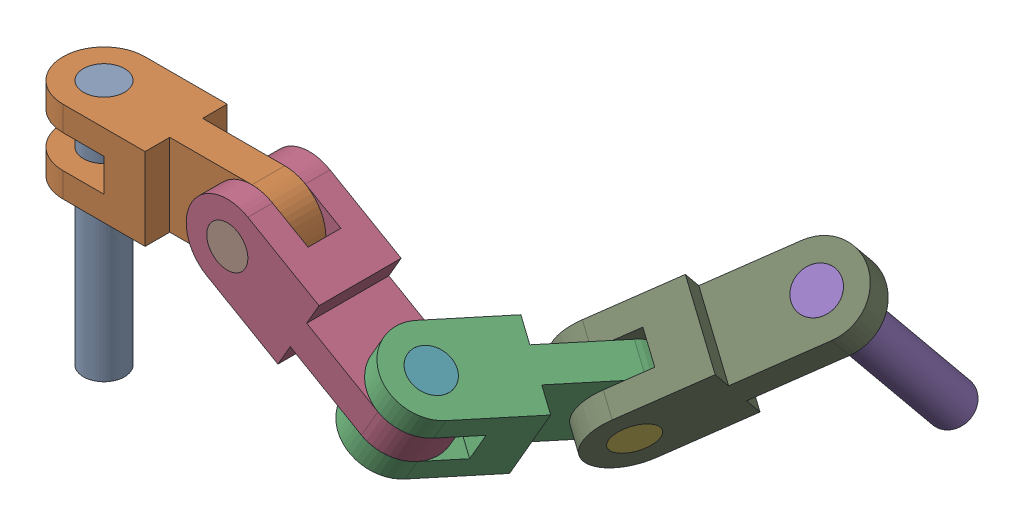
SolidWorks assembly Assemblage1 - Copie, configuration Défaut. Lengths in mm.
Overall size (693.39 349.67 575.42).
9 component instances, 3 part files, 23 mates.
Components (placement in the parent):
- long_pin-1: long_pin [Default] at origin size (50 300 50)
- chain_link-3: chain_link [Default] at (100 -50 -0.0377) x (0.000377 0 1) z (0 -1 0) size (100 300 100)
- chain_link-9: chain_link [Default] at (409.7707 -171.1309 -90.7855) x (0.785045 -0.453154 0.422322) z (-0.5 -0.866025 0.000189) size (100 300 100)
- chain_link-11: chain_link [Default] at (286.6025 -100 -0.1082) x (0.5 0.866025 -0.000189) z (0.000377 0 1) size (100 300 100)
- long_pin-4: long_pin [Default] at (570.6584 -84.4352 -296.8311) x (0.994878 -0.094996 -0.034553) z (-0.034553 -0.640821 0.766913) size (50 300 50)
- short_pin-5: short_pin [Default] at (407.084 -169.6041 -202.5461) x (0.575891 0.785045 -0.228153) z (-0.228153 0.422322 0.877263) size (50 100 50)
- short_pin-6: short_pin [Default] at (398.2051 -106.6987 -0.1503) x (0.866025 -0.5 0.000051) z (0.000051 0.000189 1) size (50 100 50)
- short_pin-7: short_pin [Default] at (199.9811 -50 -50.0755) x (1 0.000377 -0.000377) z (-0.000377 1 0) size (50 100 50)
- chain_link-13: chain_link [Default] at (507.5474 -145.9664 -245.5388) x (0.094996 0.761791 0.640821) z (0.785045 -0.453154 0.422322) size (100 300 100)
Mates (geometry in assembly coordinates):
- Coaxiale7: concentric anti-aligned: cylinder of long_pin-1 through (0 -300 0) axis (0 1 0) radius 25; cylinder of chain_link-3 through (0 0 0) axis (0 -1 0) radius 25
- Coïncidente2: coincident aligned: plane of long_pin-1 through (0 0 0) normal (0 1 0); plane of chain_link-3 through (0 0 0) normal (0 1 0)
- Perpendiculaire1: perpendicular: cylinder of long_pin-1 through (0 -300 0) axis (0 1 0) radius 25; line of chain_link-3 through (200.0075 0 19.9245) axis (-1 0 0.000377)
- Perpendiculaire2: perpendicular: cylinder of long_pin-1 through (0 -300 0) axis (0 1 0) radius 25; line of chain_link-3 through (200.0075 0 19.9245) axis (-1 0 0.000377)
- Coïncidente30: coincident anti-aligned: plane of chain_link-3 through (199.9924 -50 -20.0755) normal (-0.000377 0 -1); plane of chain_link-11 through (131.6912 -68.3013 -20.0497) normal (0.000377 0 1)
- Coïncidente31: coincident anti-aligned: plane of chain_link-3 through (200.0075 -50 19.9245) normal (0.000377 0 1); plane of chain_link-11 through (131.7063 -68.3013 19.9503) normal (-0.000377 0 -1)
- Coaxiale10: concentric anti-aligned: cylinder of chain_link-11 through (199.9811 -50 -50.0755) axis (0.000377 0 1) radius 25; circle of short_pin-7
- Coïncidente33: coincident anti-aligned: cylinder of chain_link-3 through (199.9811 -50 -50.0755) axis (0.000377 0 1) radius 25; circle of short_pin-7
- Coïncidente34: coincident aligned: plane of chain_link-11 through (199.9811 -50 -50.0755) normal (-0.000377 0 -1); plane of short_pin-7 through (199.9811 -50 -50.0755) normal (-0.000377 0 -1)
- Angle10: planar angle = 2.617994 rad anti-aligned: plane of chain_link-11 through (311.6214 -56.6987 49.8824) normal (0.5 0.866025 -0.000189); plane of chain_link-3 through (0 0 0) normal (0 1 0)
- Coïncidente37: coincident anti-aligned: plane of chain_link-9 through (325.67 -99.4563 24.0616) normal (-0.5 -0.866025 0.000189); plane of chain_link-11 through (383.2051 -132.6795 -0.1446) normal (0.5 0.866025 -0.000189)
- Coaxiale11: concentric anti-aligned: cylinder of chain_link-9 through (398.2051 -106.6987 -0.1503) axis (-0.5 -0.866025 0.000189) radius 25; cylinder of chain_link-11 through (348.205 -193.3013 -0.1314) axis (0.5 0.866025 -0.000189) radius 25
- Coaxiale12: concentric anti-aligned: cylinder of chain_link-9 through (398.2051 -106.6987 -0.1503) axis (-0.5 -0.866025 0.000189) radius 25; cylinder of short_pin-6 through (348.2051 -193.3013 -0.1314) axis (0.5 0.866025 -0.000189) radius 25
- Coïncidente38: coincident aligned: plane of chain_link-9 through (348.2051 -193.3013 -0.1314) normal (-0.5 -0.866025 0.000189); plane of short_pin-6 through (348.2051 -193.3013 -0.1314) normal (-0.5 -0.866025 0.000189)
- Angle11: planar angle = 2.007129 rad anti-aligned: plane of chain_link-11 through (199.9811 -50 -50.0755) normal (-0.000377 0 -1); plane of chain_link-9 through (345.5184 -191.7745 -111.8921) normal (-0.785045 0.453154 -0.422322)
- Coïncidente46: coincident anti-aligned: plane of chain_link-9 through (430.6354 -183.1987 -189.8765) normal (-0.785045 0.453154 -0.422322); plane of chain_link-13 through (395.28 -244.436 -189.8631) normal (0.785045 -0.453154 0.422322)
- Coïncidente47: coincident anti-aligned: plane of chain_link-9 through (462.0372 -201.3249 -172.9836) normal (0.785045 -0.453154 0.422322); plane of chain_link-13 through (426.6818 -262.5621 -172.9703) normal (-0.785045 0.453154 -0.422322)
- Coaxiale15: concentric aligned: cylinder of chain_link-9 through (407.084 -169.6041 -202.5461) axis (0.785045 -0.453154 0.422322) radius 25; cylinder of chain_link-13 through (407.084 -169.6041 -202.5461) axis (0.785045 -0.453154 0.422322) radius 25
- Coaxiale16: concentric anti-aligned: cylinder of short_pin-5 through (485.5885 -214.9195 -160.3139) axis (-0.785045 0.453154 -0.422322) radius 25; cylinder of chain_link-13 through (407.084 -169.6041 -202.5461) axis (0.785045 -0.453154 0.422322) radius 25
- Coïncidente48: coincident aligned: plane of short_pin-5 through (407.084 -169.6041 -202.5461) normal (-0.785045 0.453154 -0.422322); plane of chain_link-13 through (407.084 -169.6041 -202.5461) normal (-0.785045 0.453154 -0.422322)
- Angle13: planar angle = 3.926991 rad anti-aligned: plane of chain_link-9 through (398.2051 -106.6987 -0.1503) normal (0.5 0.866025 -0.000189); plane of chain_link-13 through (551.5494 -130.5346 -192.3817) normal (0.094996 0.761791 0.640821)
- Coaxiale17: concentric aligned: cylinder of long_pin-4 through (542.1598 -312.9723 -489.0773) axis (0.094996 0.761791 0.640821) radius 25; cylinder of chain_link-13 through (564.0087 -137.7605 -341.6886) axis (0.094996 0.761791 0.640821) radius 25
- Coïncidente50: coincident aligned: plane of long_pin-4 through (570.6584 -84.4352 -296.8311) normal (0.094996 0.761791 0.640821); plane of chain_link-13 through (570.6584 -84.4352 -296.8311) normal (0.094996 0.761791 0.640821)
